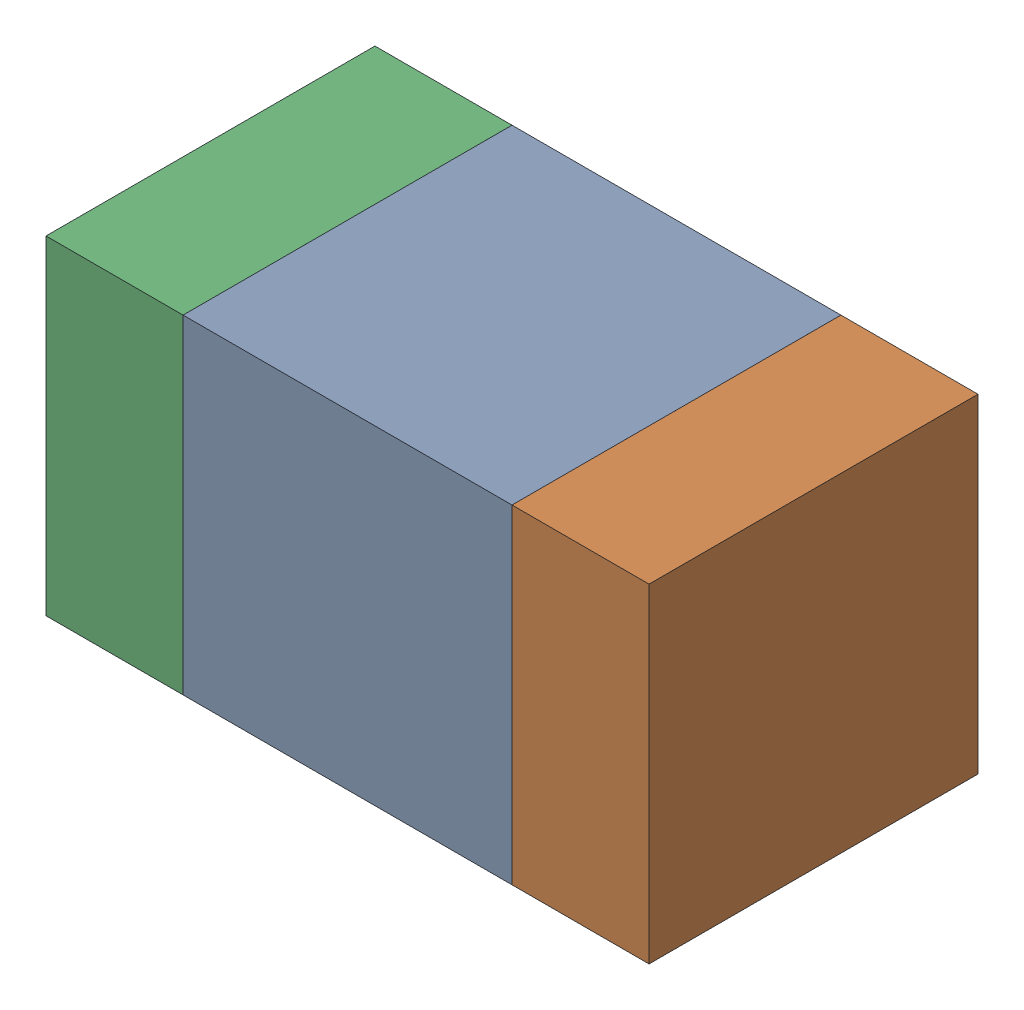
SolidWorks assembly C310_1PCB, configuration Default. Lengths in mm.
Overall size (1.1 0.6 0.6).
6 component instances, 2 part files, 0 mates.
Components (placement in the parent):
- 761606048-1: 761606048 [Default] at (140.2 112.9 0) size (0.6 0.6 0.6)
  - Extruded_9-1: Extruded_9 [Default] at origin size (0.6 0.6 0.6)
- 854785160-1: 854785160 [Default] at (140.625 112.9 0) size (0.25 0.6 0.6)
  - Extruded_19-1: Extruded_19 [Default] at origin size (0.25 0.6 0.6)
- 854785160-2: 854785160 [Default] at (139.775 112.9 0) size (0.25 0.6 0.6)
  - Extruded_19-1: Extruded_19 [Default] at origin size (0.25 0.6 0.6)
